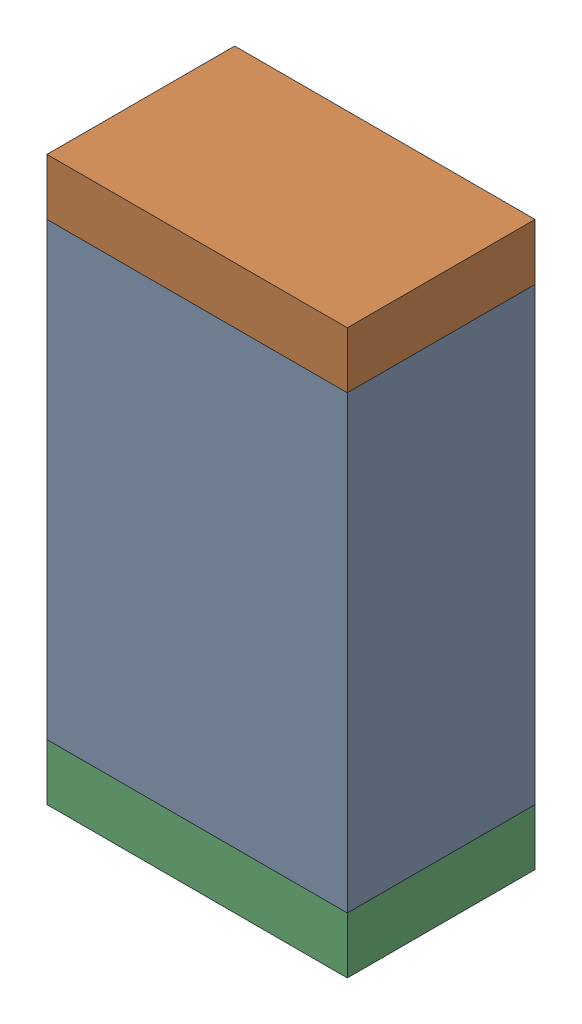
SolidWorks assembly C59, configuration Default. Lengths in mm.
Overall size (0.8 1.5 0.5).
6 component instances, 2 part files, 0 mates.
Components (placement in the parent):
- 810156976-1: 810156976 [Default] at (127.45 53 0) size (0.8 1.2 0.5)
  - Extruded_6-1: Extruded_6 [Default] at origin size (0.8 1.2 0.5)
- 810156592-1: 810156592 [Default] at (127.45 53.675 0) size (0.8 0.15 0.5)
  - Extruded_7-1: Extruded_7 [Default] at origin size (0.8 0.15 0.5)
- 810156592-2: 810156592 [Default] at (127.45 52.325 0) size (0.8 0.15 0.5)
  - Extruded_7-1: Extruded_7 [Default] at origin size (0.8 0.15 0.5)
